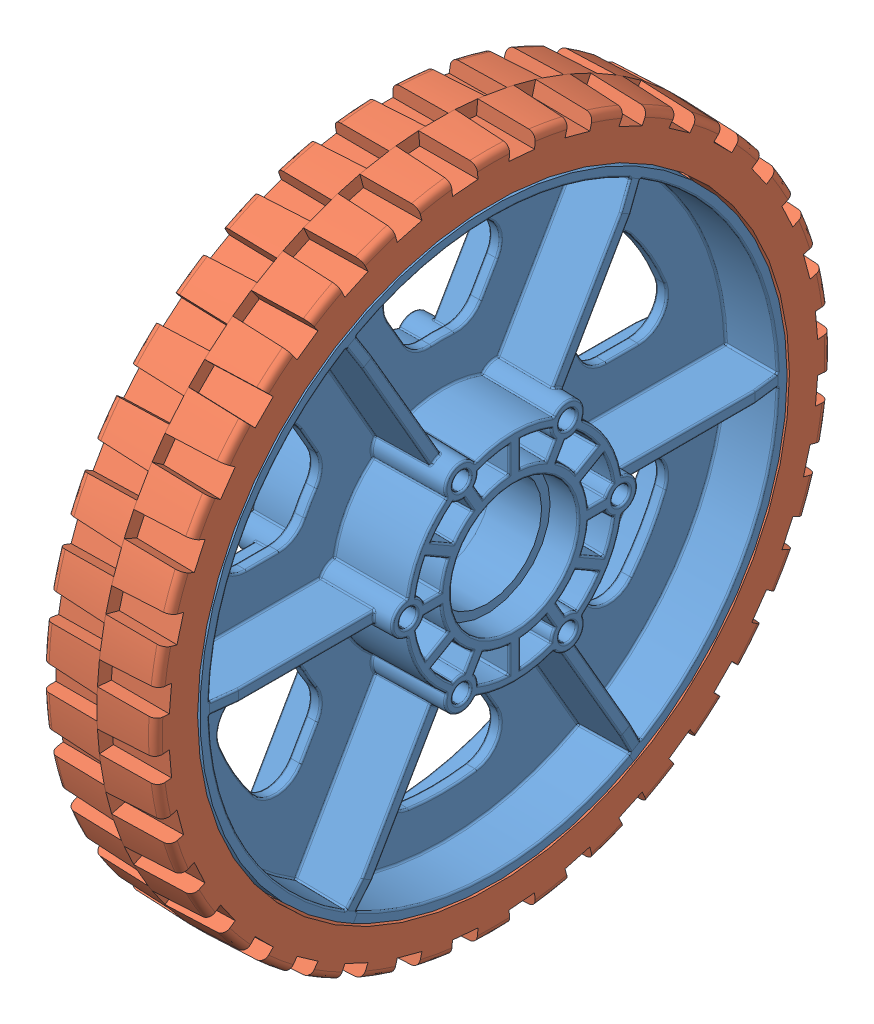
SolidWorks assembly 6 HiGrip Asm Rev II, configuration Default. Lengths in mm.
Overall size (35.05 152.4 152.4).
2 component instances, 2 part files, 2 mates.
Components (placement in the parent):
- 6 wheel Rev 4-1: 6 wheel Rev 4 [Default] at (-52.6446 9.4231 21.378) size (35.05 132.08 132.08)
- 6 wheel tread II-1: 6 wheel tread II [Default] at (-65.3446 9.4231 21.378) x (0 0 -1) z (1 0 0) size (152.4 152.4 25.58)
Mates (geometry in assembly coordinates):
- Concentric1: concentric anti-aligned: circle of 6 wheel Rev 4-1; circle of 6 wheel tread II-1
- Coincident1: coincident aligned: plane of 6 wheel Rev 4-1 through (-39.9446 9.4231 21.378) normal (1 0 0); plane of 6 wheel tread II-1 through (-39.9446 9.4231 87.672) normal (1 0 0)
